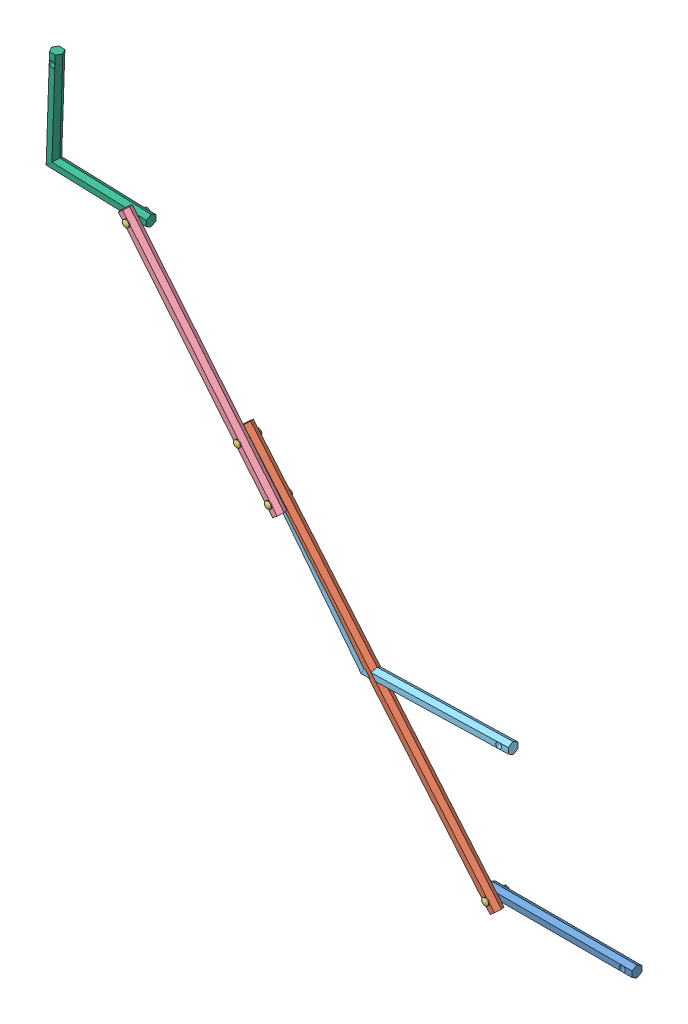
SolidWorks assembly Assem4, configuration Valor predeterminado. Lengths in mm.
Overall size (595.37 543.92 34.4).
9 component instances, 6 part files, 16 mates.
Components (placement in the parent):
- Eixo 1 150mm-1: Eixo 1 150mm [Valor predeterminado] at origin size (150 11.55 10)
- Eixo 2 400mm-1: Eixo 2 400mm [Valor predeterminado] at (-187.5453 145.1987 10.2) x (0.644975 -0.764203 0) z (0 0 1) size (400 11.55 10)
- pino-1: pino [Valor predeterminado] at (-65 0 5.1) x (1 0 0) z (0 1 0) size (7 24.2 7)
- Eixo 3 250 mm 3 furos-1: Eixo 3 250 mm 3 furos [Valor predeterminado] at (-351.3894 340.591 20.4) x (-0.635366 0.772211 0) z (0 0 1) size (250 11.55 10)
- pino-2: pino [Valor predeterminado] at (-278.3223 251.7868 15.3) x (1 -0.000056 0) z (-0.000056 -1 0) size (7 24.2 7)
- pino-3: pino [Valor predeterminado] at (-310.0906 290.3973 15.3) x (1 -0.000027 0) z (0.000027 1 0) size (7 24.2 7)
- Eixo 4 em V-1: Eixo 4 em V [Default] at (-192.0298 141.5433 10.2) x (0.999633 0.027082 0) z (-0.027082 0.999633 0) size (243.86 10 129.79)
- eixo 5 L-1: eixo 5 L [Valor predeterminado] at (-514.4057 432.417 10.2) x (0.033574 0.999436 0) z (-0.999436 0.033574 0) size (105.77 10 105.77)
- pino-4: pino [Valor predeterminado] at (-424.4564 429.3953 15.3) x (1 0.000061 0) z (0.000061 -1 0) size (7 24.2 7)
Mates (geometry in assembly coordinates):
- Concentric1: concentric: cylinder of assembly; cylinder of assembly; cylinder of Eixo 1 150mm-1 through (-65 0 -5) axis (0 0 1) radius 3; cylinder of Eixo 2 400mm-1 through (-65 0 5.2) axis (0 0 1) radius 3
- Concentric2: concentric: cylinder of assembly; cylinder of assembly; cylinder of Eixo 1 150mm-1 through (-65 0 -5) axis (0 0 1) radius 3; cylinder of pino-1 through (-65 0 -0.8508) axis (0 0 -1) radius 3
- Coincident1: coincident: plane of assembly; plane of assembly; plane of Eixo 2 400mm-1 through (-56.3442 -5.7802 15.2) normal (0 0 1); plane of pino-1 through (-65 0 15.2) normal (0 0 -1)
- Coincident2: coincident: plane of assembly; plane of assembly; plane of Eixo 1 150mm-1 through (75 -2.8868 -5) normal (0 0 -1); plane of pino-1 through (-65 0 -5) normal (0 0 1)
- Concentric3: concentric: cylinder of assembly; cylinder of assembly; cylinder of Eixo 2 400mm-1 through (-310.0906 290.3973 5.2) axis (0 0 1) radius 3; cylinder of Eixo 3 250 mm 3 furos-1 through (-310.0906 290.3973 15.4) axis (0 0 1) radius 3
- Concentric4: concentric: cylinder of assembly; cylinder of assembly; cylinder of Eixo 2 400mm-1 through (-310.0906 290.3973 5.2) axis (0 0 1) radius 3; cylinder of pino-3 through (-310.0906 290.3973 9.3492) axis (0 0 -1) radius 3
- Coincident3: coincident: plane of assembly; plane of assembly; plane of Eixo 3 250 mm 3 furos-1 through (-433.0393 435.2833 25.4) normal (0 0 1); plane of pino-3 through (-310.0906 290.3973 25.4) normal (0 0 -1)
- Coincident4: coincident: plane of assembly; plane of assembly; plane of Eixo 2 400mm-1 through (-60.7563 -9.5039 5.2) normal (0 0 -1); plane of pino-3 through (-310.0906 290.3973 5.2) normal (0 0 1)
- Concentric5: concentric: cylinder of assembly; cylinder of assembly; cylinder of Eixo 3 250 mm 3 furos-1 through (-278.3223 251.7868 15.4) axis (0 0 1) radius 3; cylinder of Eixo 4 em V-1 through (-278.3223 251.7868 15.2) axis (0 0 -1) radius 3
- Concentric6: concentric: cylinder of assembly; cylinder of assembly; cylinder of pino-2 through (-278.3223 251.7868 21.2508) axis (0 0 1) radius 3; cylinder of Eixo 4 em V-1 through (-278.3223 251.7868 15.2) axis (0 0 -1) radius 3
- Coincident5: coincident: circle of assembly; plane of assembly; circle of pino-2; plane of Eixo 4 em V-1 through (-187.7219 140.7232 5.2) normal (0 0 -1)
- Coincident6: coincident: plane of assembly; plane of assembly; plane of Eixo 3 250 mm 3 furos-1 through (-433.0393 435.2833 25.4) normal (0 0 1); plane of pino-2 through (-278.3223 251.7868 25.4) normal (0 0 -1)
- Concentric7: concentric: cylinder of assembly; cylinder of assembly; cylinder of Eixo 3 250 mm 3 furos-1 through (-424.4564 429.3953 15.4) axis (0 0 1) radius 3; cylinder of eixo 5 L-1 through (-424.4564 429.3953 15.2) axis (0 0 -1) radius 3
- Concentric8: concentric: cylinder of assembly; cylinder of assembly; cylinder of eixo 5 L-1 through (-424.4564 429.3953 15.2) axis (0 0 -1) radius 3; cylinder of pino-4 through (-424.4564 429.3953 21.2508) axis (0 0 1) radius 3
- Coincident7: coincident: plane of assembly; plane of assembly; plane of eixo 5 L-1 through (-414.3652 431.9447 5.2) normal (0 0 -1); plane of pino-4 through (-424.4564 429.3953 5.2) normal (0 0 1)
- Coincident8: coincident: plane of assembly; plane of assembly; plane of Eixo 3 250 mm 3 furos-1 through (-433.0393 435.2833 25.4) normal (0 0 1); plane of pino-4 through (-424.4564 429.3953 25.4) normal (0 0 -1)
